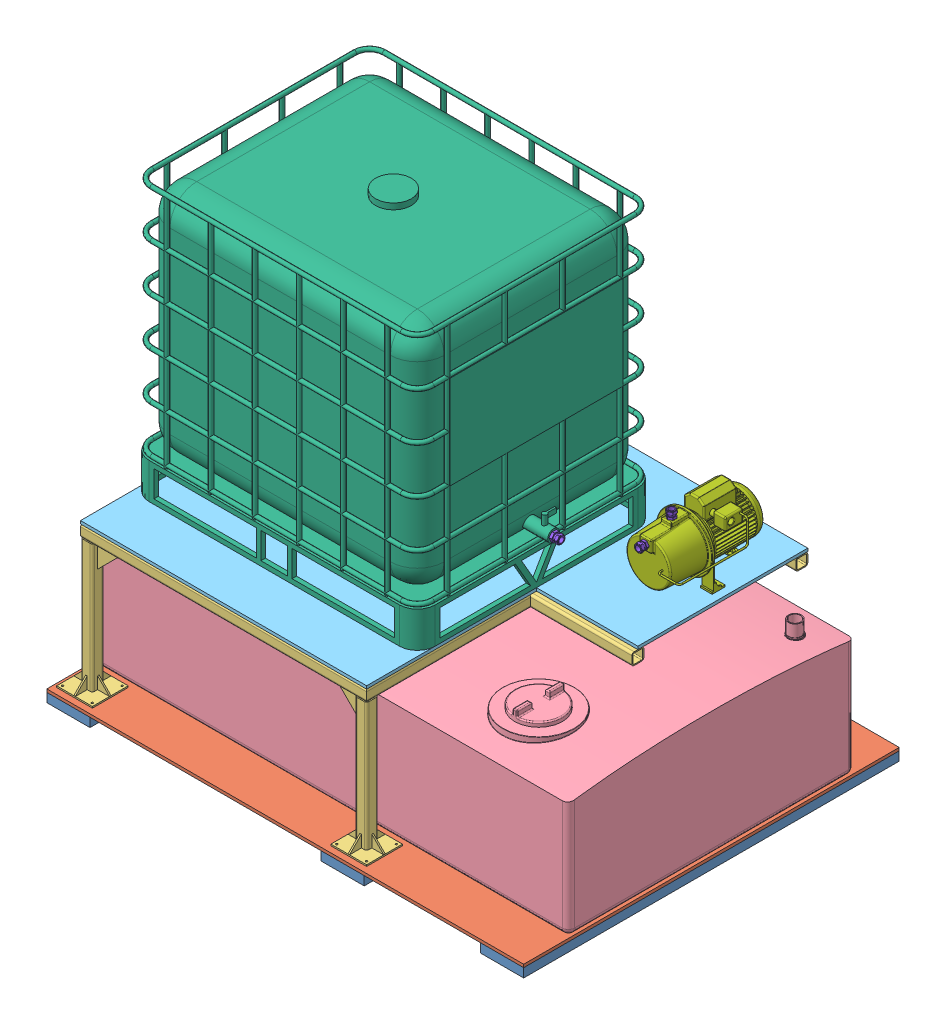
SolidWorks assembly 20ft_Tankpump_assembly, configuration Default. Lengths in mm.
Overall size (2032 1835.15 1600.2).
10 component instances, 8 part files, 23 mates.
Components (placement in the parent):
- Support_Structure_Woodbase-1: Support_Structure_Woodbase [Default<As Machined>] at (-49.7299 1126.5779 2253.8241) size (2032 38.1 1600.2)
- Support_Structure_PlywoodBase-1: Support_Structure_PlywoodBase [Default] at (-141.8049 1145.6279 2253.8241) size (2032 12.7 1600.2)
- Finalized_Support_Structure-1: Finalized_Support_Structure [Default<As Machined>] at (-49.7299 1736.1779 754.4176) x (0 0 1) z (-1 0 0) size (1549.4 603.25 1701.8)
- Tank-20ft-Waste-1: Tank-20ft-Waste [Default] at (1890.1951 1158.3279 2063.3241) size (2032 577.68 1219.2)
- Support_Structure_PlywoodFreshbase-1: Support_Structure_PlywoodFreshbase [Default] at (-75.1299 1761.5779 2176.8176) size (1651 12.7 1447.8)
- Tank-20ft-Fresh-1: Tank-20ft-Fresh [Default] at (534.4701 1774.2779 1452.9176) x (0 0 -1) z (1 0 0) size (1016 1168.4 1292.1)
- Pump-1: Pump [Detailed] at (1423.4701 1908.8979 1090.9676) size (273.44 283.66 433.45)
- solidworks-lok male connector-1: solidworks-lok male connector [MALE CONNECTOR-0.875Tx0.750 NPT] at (1423.4701 2007.1408 1157.6426) x (0 -1 0) z (0 0 -1) size (60.55 31.75 36.66)
- solidworks-lok male connector-3: solidworks-lok male connector [MALE CONNECTOR-0.875Tx1 NPT] at (1193.0921 2002.8779 1452.9176) x (-1 0 0) z (0 -0.924225 -0.381849) size (67.15 34.92 40.33)
- solidworks-lok male connector-5: solidworks-lok male connector [MALE CONNECTOR-0.875Tx0.750 NPT] at (1423.4701 1982.3963 1249.9716) x (0 0 -1) z (1 0 0) size (60.55 31.75 36.66)
Mates (geometry in assembly coordinates):
- Coincident1: coincident anti-aligned: line of Support_Structure_Woodbase-1 through (42.3451 1145.6279 2253.8241) axis (-1 0 0); line of Support_Structure_PlywoodBase-1 through (-141.8049 1145.6279 2253.8241) axis (1 0 0)
- Coincident2: coincident aligned: line of Support_Structure_Woodbase-1 through (1890.1951 1145.6279 2253.8241) axis (0 0 -1); line of Support_Structure_PlywoodBase-1 through (1890.1951 1145.6279 2253.8241) axis (0 0 -1)
- Coincident3: coincident anti-aligned: plane of Support_Structure_PlywoodBase-1 through (-141.8049 1158.3279 2253.8241) normal (0 1 0); plane of Finalized_Support_Structure-1 through (-49.7299 1158.3279 754.4176) normal (0 -1 0)
- Distance1: distance = 25.4 mm: line of Finalized_Support_Structure-1 through (-125.9299 1164.6779 678.2176) axis (1 0 0); line of Support_Structure_PlywoodBase-1 through (1890.1951 1158.3279 653.6241) axis (-1 0 0)
- Distance4: distance = 15.875 mm: line of Support_Structure_PlywoodBase-1 through (-141.8049 1158.3279 653.6241) axis (0 0 1); line of Finalized_Support_Structure-1 through (-125.9299 1158.3279 2227.6176) axis (0 0 -1)
- Coincident12: coincident aligned: plane of Support_Structure_PlywoodBase-1 through (-141.8049 1158.3279 2253.8241) normal (0 1 0); plane of Tank-20ft-Waste-1 through (1890.1951 1158.3279 2063.3241) normal (0 1 0)
- Coincident14: coincident: line of Support_Structure_PlywoodBase-1 through (-141.8049 1158.3279 653.6241) axis (0 0 1); plane of Tank-20ft-Waste-1 through (-141.8049 1413.6314 1453.7241) normal (-1 0 0)
- Distance6: distance = 609.6 mm: line of Support_Structure_Woodbase-1 through (-49.7299 1126.5779 1453.7241) axis (1 0 0); plane of Tank-20ft-Waste-1 through (-141.8049 1158.3279 844.1241) normal (0 0 -1)
- Coincident16: coincident anti-aligned: plane of Finalized_Support_Structure-1 through (1575.8701 1761.5779 738.5426) normal (0 1 0); plane of Support_Structure_PlywoodFreshbase-1 through (-75.1299 1761.5779 2176.8176) normal (0 -1 0)
- Coincident17: coincident: plane of Finalized_Support_Structure-1 through (-75.1299 1720.3029 2151.4176) normal (-1 0 0); line of Support_Structure_PlywoodFreshbase-1 through (-75.1299 1761.5779 729.0176) axis (0 0 1)
- Coincident18: coincident: plane of Finalized_Support_Structure-1 through (1575.8701 1752.0529 729.0176) normal (0 0 -1); line of Support_Structure_PlywoodFreshbase-1 through (1575.8701 1761.5779 729.0176) axis (-1 0 0)
- Coincident19: coincident aligned: plane of Support_Structure_PlywoodFreshbase-1 through (-75.1299 1774.2779 2176.8176) normal (0 1 0); plane of Tank-20ft-Fresh-1 through (534.4701 1774.2779 1452.9176) normal (0 1 0)
- Coincident20: coincident anti-aligned: line of Support_Structure_PlywoodFreshbase-1 through (-75.1299 1774.2779 729.0176) axis (0 0 1); line of Tank-20ft-Fresh-1 through (-75.1299 1774.2779 1884.7176) axis (0 0 -1)
- Coincident22: coincident: line of Finalized_Support_Structure-1 through (-49.7299 1736.1779 1452.9176) axis (1 0 0); plane of Tank-20ft-Fresh-1 through (534.4701 1774.2779 1452.9176) normal (0 0 -1)
- Coincident23: coincident aligned: plane of Support_Structure_PlywoodFreshbase-1 through (-75.1299 1774.2779 2176.8176) normal (0 1 0); plane of Pump-1 through (1423.4701 1774.2779 1090.9676) normal (0 1 0)
- Distance8: distance = 152.4 mm: plane of Pump-1 through (1423.4701 1908.8979 1090.9676) normal (1 0 0); line of Support_Structure_PlywoodFreshbase-1 through (1575.8701 1774.2779 1452.9176) axis (0 0 -1)
- Distance9: distance = 361.95 mm: plane of Pump-1 through (1423.4701 1908.8979 1090.9676) normal (0 0 1); line of Finalized_Support_Structure-1 through (-49.7299 1736.1779 1452.9176) axis (1 0 0)
- Concentric1: concentric aligned: circle of Pump-1; circle of solidworks-lok male connector-1
- Coincident24: coincident anti-aligned: plane of Pump-1 through (1401.2451 2026.1908 1179.8676) normal (0 1 0); plane of solidworks-lok male connector-1 through (1423.4701 2026.1908 1140.2282) normal (0 -1 0)
- Concentric2: concentric aligned: circle of Tank-20ft-Fresh-1; circle of solidworks-lok male connector-3
- Coincident25: coincident anti-aligned: plane of Tank-20ft-Fresh-1 through (1216.9681 2002.8779 1452.9176) normal (1 0 0); plane of solidworks-lok male connector-3 through (1216.9681 1984.2419 1445.218) normal (-1 0 0)
- Concentric3: concentric aligned: circle of Pump-1; circle of solidworks-lok male connector-5
- Coincident26: coincident anti-aligned: plane of Pump-1 through (1423.4701 1908.8979 1269.0216) normal (0 0 1); plane of solidworks-lok male connector-5 through (1440.8844 1982.3963 1269.0216) normal (0 0 -1)
